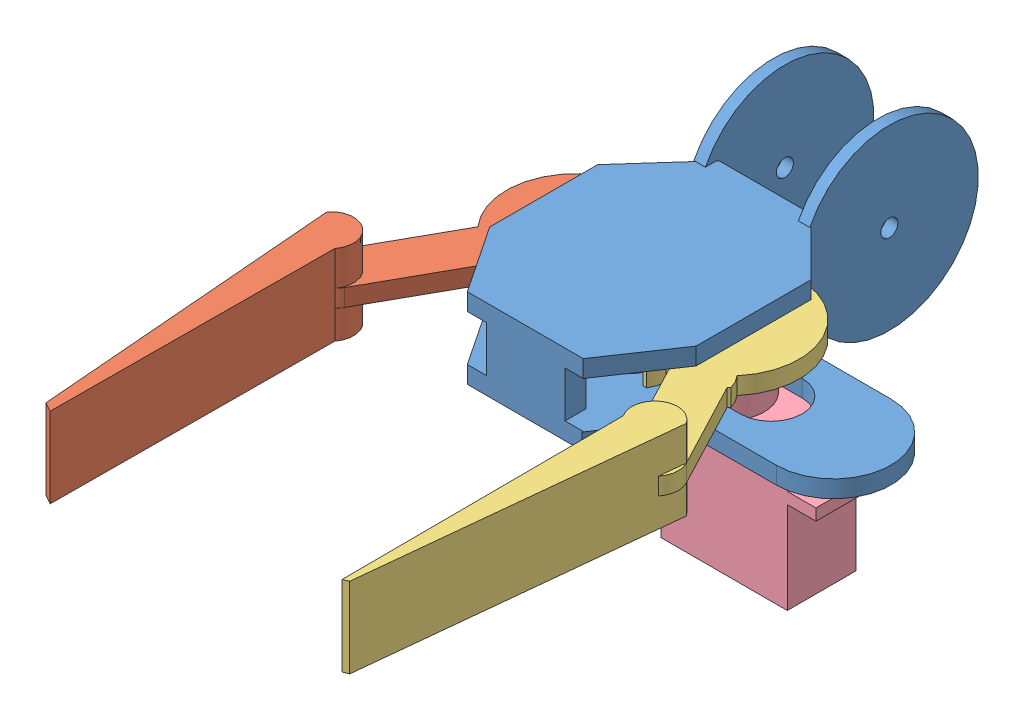
SolidWorks assembly Assem1, configuration Default. Lengths in mm.
Overall size (114.11 44.53 126.4).
4 component instances, 4 part files, 8 mates.
Components (placement in the parent):
- grip2-1: grip2 [Default] at (-23.4355 -8.246 23.6192) size (60 31.06 69.16)
- Gear 1-1: Gear 1 [Default] at (-23.3605 -0.246 7.4443) x (-0.487316 0 0.873226) z (-0.873226 0 -0.487316) size (88.86 14 39.75)
- Gear 2-1: Gear 2 [Default] at (4.7269 -0.246 -10.7707) x (-0.369826 0 -0.929101) z (0.929101 0 -0.369826) size (91.37 14 30.68)
- Servo Motor 6-1: Servo Motor 6 [Default] at (24.4645 -30.246 -7.3808) x (-1 0 0) z (0 0 -1) size (32 27 12)
Mates (geometry in assembly coordinates):
- Distance14: distance = 5 mm anti-aligned: plane of grip2-1 through (-51.9132 -5.246 1.1192) normal (0 1 0); plane of Gear 1-1 through (-33.4205 -0.246 25.4708) normal (0 -1 0)
- Concentric19: concentric aligned: cylinder of grip2-1 through (-18.4355 -5.246 -1.3808) axis (0 -1 0) radius 1.5; cylinder of Gear 1-1 through (-18.4355 2.754 -1.3808) axis (0 -1 0) radius 1.5
- Distance15: distance = 5 mm anti-aligned: plane of Gear 2-1 through (-2.9077 -0.246 -29.9507) normal (0 -1 0); plane of grip2-1 through (-51.9132 -5.246 1.1192) normal (0 1 0)
- Concentric23: concentric aligned: cylinder of grip2-1 through (8.4645 -8.246 -1.3808) axis (0 -1 0) radius 5.4; cylinder of Gear 2-1 through (8.4645 2.754 -1.3808) axis (0 -1 0) radius 1.5
- GearMate1: gear = 24.1855 : 24.1855 mm: cylinder of Gear 1-1 through (-18.4355 2.754 -1.3808) axis (0 -1 0) radius 12.0927; cylinder of Gear 2-1 through (8.4645 2.754 -1.3808) axis (0 -1 0) radius 12.0927
- Coincident33: coincident anti-aligned: plane of grip2-1 through (-51.9132 -8.246 1.1192) normal (0 -1 0); plane of Servo Motor 6-1 through (24.4645 -8.246 4.6192) normal (0 1 0)
- Concentric37: concentric aligned: circle of Gear 2-1; circle of Servo Motor 6-1
- Parallel2: parallel aligned: plane of grip2-1 through (-23.4355 -5.246 1.1192) normal (-1 0 0); plane of Servo Motor 6-1 through (-2.5355 -12.246 4.6192) normal (-1 0 0)
